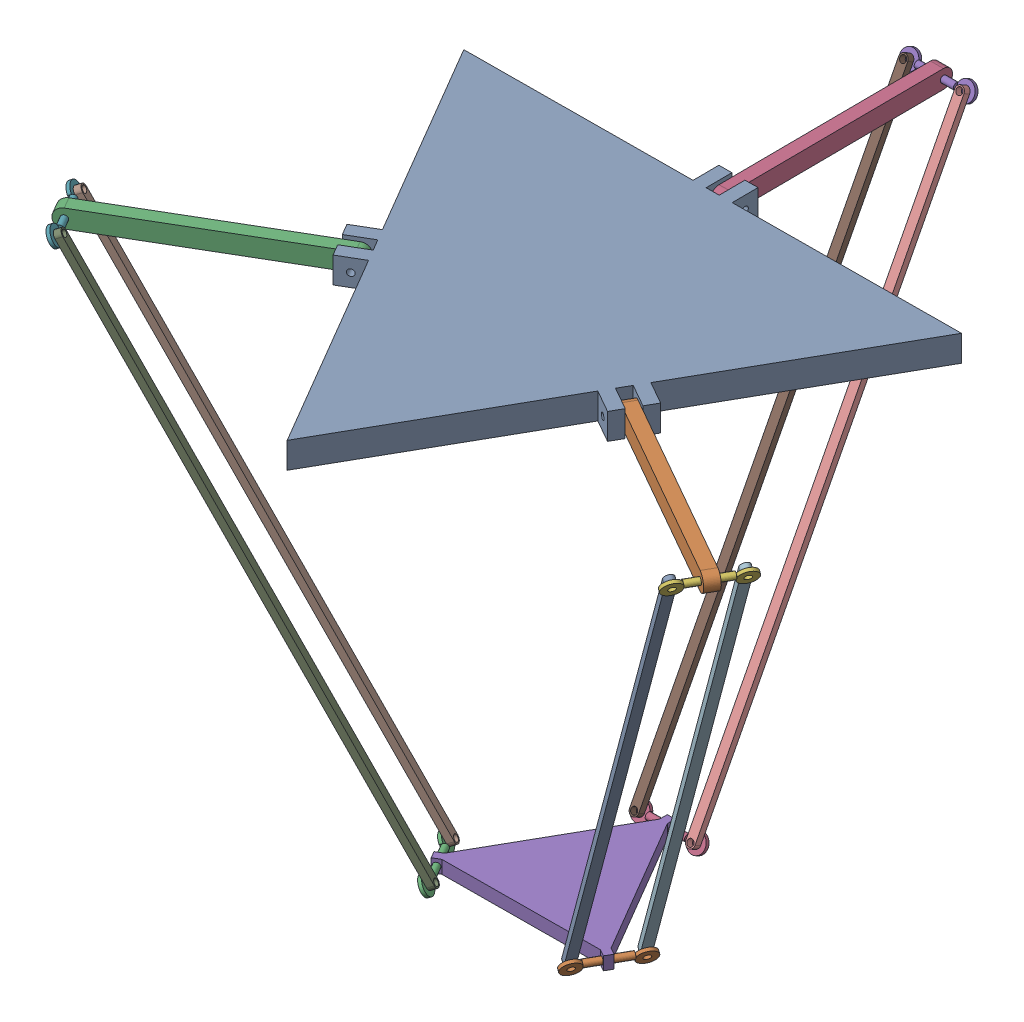
SolidWorks assembly deltafinal, configuration Default. Lengths in mm.
Overall size (529.94 413.54 512.31).
17 component instances, 5 part files, 44 mates.
Components (placement in the parent):
- Base_triangulo_cima-1: Base_triangulo_cima [Default] at (0 -20 0) x (0.999979 0 -0.006522) z (0.006522 0 0.999979) size (381.1 20 350.04)
- Barra_cima-1: Barra_cima [Default] at (104.3244 -10 59.3279) x (0.869268 0 0.494341) z (-0.494341 0 0.869268) size (178 14 10)
- Barra_cima-2: Barra_cima [Default] at (-245.0321 -10 143.6081) x (0.862746 0 -0.505637) z (0.505637 0 0.862746) size (178 14 10)
- Barra_cima-3: Barra_cima [Default] at (-1.8523 -10 -284.0081) x (0.006522 0 0.999979) z (-0.999979 0 0.006522) size (178 14 10)
- entre_barras1-1: entre_barras1 [Default] at (-1.8523 -10 -284.0081) x (0.999979 0 -0.006522) z (0.005767 0.466869 0.884308) size (57.08 14 5)
- entre_barras1-2: entre_barras1 [Default] at (246.8843 -10 140.3999) x (-0.494341 0 0.869268) z (-0.768717 0.466869 -0.437159) size (57.08 14 5)
- entre_barras1-3: entre_barras1 [Default] at (-245.0321 -10 143.6081) x (-0.505637 0 -0.862746) z (0.762949 0.466869 -0.447149) size (57.08 14 5)
- Barra_baixo-1: Barra_baixo [Default] at (-254.0153 -8.8328 123.9081) x (0.506087 -0.000987 0.862482) z (-0.762949 -0.466869 0.447149) size (7 455 5)
- Barra_baixo-2: Barra_baixo [Default] at (-232.2341 -8.8328 161.0724) x (0.506087 -0.000987 0.862482) z (-0.762949 -0.466869 0.447149) size (7 455 5)
- Barra_baixo-3: Barra_baixo [Default] at (19.7 -8.8328 -281.9378) x (0.999975 0.000987 -0.007043) z (0.005767 0.466869 0.884308) size (7 455 5)
- Barra_baixo-4: Barra_baixo [Default] at (-23.3757 -8.8328 -281.6568) x (0.999975 0.000987 -0.007043) z (0.005767 0.466869 0.884308) size (7 455 5)
- Barra_baixo-5: Barra_baixo [Default] at (255.6098 -8.8328 120.5844) x (0.494794 0.000987 -0.86901) z (0.768717 -0.466869 0.437159) size (7 455 5)
- Barra_baixo-6: Barra_baixo [Default] at (234.3152 -8.8328 158.0296) x (0.494794 0.000987 -0.86901) z (0.768717 -0.466869 0.437159) size (7 455 5)
- entre_barras1-4: entre_barras1 [Default] at (65.318 -406.1781 36.5703) x (-0.494341 0 0.869268) z (-0.768717 0.466869 -0.437159) size (57.08 14 5)
- entre_barras1-5: entre_barras1 [Default] at (-64.8354 -406.1781 37.4191) x (-0.505637 0 -0.862746) z (0.762949 0.466869 -0.447149) size (57.08 14 5)
- entre_barras1-6: entre_barras1 [Default] at (0.0118 -406.1781 -74.8587) x (0.999979 0 -0.006522) z (0.005767 0.466869 0.884308) size (57.08 14 5)
- base_baixo-1: base_baixo [Default] at (0.2513 -411.1781 38.5258) x (0.999979 0 -0.006522) z (0.006522 0 0.999979) size (137.85 10 119.38)
Mates (geometry in assembly coordinates):
- Concentric1: concentric anti-aligned: cylinder of Base_triangulo_cima-1 through (115.235 -10 40.1423) axis (-0.494341 0 0.869268) radius 2.5; cylinder of Barra_cima-1 through (101.8527 -10 63.6743) axis (0.494341 0 -0.869268) radius 2.5
- Concentric2: concentric anti-aligned: cylinder of Base_triangulo_cima-1 through (115.235 -10 40.1423) axis (-0.494341 0 0.869268) radius 2.5; cylinder of Barra_cima-1 through (101.8527 -10 63.6743) axis (0.494341 0 -0.869268) radius 2.5
- Coincident1: coincident anti-aligned: plane of Base_triangulo_cima-1 through (110.5454 0 68.6177) normal (0.494341 0 -0.869268); plane of Barra_cima-1 through (101.8527 -10 63.6743) normal (-0.494341 0 0.869268)
- Concentric3: concentric anti-aligned: cylinder of Base_triangulo_cima-1 through (-229.181 -10 -153.6891) axis (0.505637 0 0.862746) radius 2.5; cylinder of Barra_cima-2 through (-101.0135 -10 64.9973) axis (-0.505637 0 -0.862746) radius 2.5
- Concentric4: concentric anti-aligned: cylinder of Base_triangulo_cima-1 through (-229.181 -10 -153.6891) axis (0.505637 0 0.862746) radius 2.5; cylinder of Barra_cima-2 through (-101.0135 -10 64.9973) axis (-0.505637 0 -0.862746) radius 2.5
- Coincident2: coincident anti-aligned: plane of Base_triangulo_cima-1 through (-114.6973 0 61.4263) normal (0.505637 0 0.862746); plane of Barra_cima-2 through (-247.5602 -10 139.2944) normal (-0.505637 0 -0.862746)
- Concentric5: concentric anti-aligned: cylinder of Base_triangulo_cima-1 through (157.691 -10 -121.0451) axis (-0.999979 0 0.006522) radius 2.5; cylinder of Barra_cima-3 through (-5.7826 -10 -119.9789) axis (0.999979 0 -0.006522) radius 2.5
- Concentric6: concentric anti-aligned: cylinder of Base_triangulo_cima-1 through (157.691 -10 -121.0451) axis (-0.999979 0 0.006522) radius 2.5; cylinder of Barra_cima-3 through (-5.7826 -10 -119.9789) axis (0.999979 0 -0.006522) radius 2.5
- Coincident3: coincident anti-aligned: plane of Base_triangulo_cima-1 through (4.152 0 -130.0439) normal (-0.999979 0 0.006522); plane of Barra_cima-3 through (3.1476 -10 -284.0407) normal (0.999979 0 -0.006522)
- Concentric8: concentric anti-aligned: cylinder of Barra_cima-3 through (-6.8522 -10 -283.9754) axis (0.999979 0 -0.006522) radius 2.5; cylinder of entre_barras1-1 through (-16.8519 -10 -283.9102) axis (-0.999979 0 0.006522) radius 2.5
- Distance2: distance = 10 mm anti-aligned: plane of entre_barras1-1 through (-16.8588 -13.378 -284.9539) normal (0.999979 0 -0.006522); plane of Barra_cima-3 through (-6.8522 -10 -283.9754) normal (-0.999979 0 0.006522)
- Concentric10: concentric aligned: cylinder of Barra_cima-1 through (244.4126 -10 144.7463) axis (0.494341 0 -0.869268) radius 2.5; cylinder of entre_barras1-2 through (254.2994 -10 127.3609) axis (0.494341 0 -0.869268) radius 2.5
- Distance3: distance = 10 mm anti-aligned: plane of entre_barras-2 through (255.2066 -13.378 127.8768) normal (-0.494341 0 0.869268); plane of Barra_cima-1 through (106.7961 -10 54.9816) normal (0.494341 0 -0.869268)
- Concentric11: concentric anti-aligned: cylinder of Barra_cima-2 through (-242.5039 -10 147.9219) axis (-0.505637 0 -0.862746) radius 2.5; cylinder of entre_barras1-3 through (-237.4475 -10 156.5493) axis (0.505637 0 0.862746) radius 2.5
- Distance4: distance = 10 mm anti-aligned: plane of entre_barras1-3 through (-238.3479 -13.378 157.077) normal (-0.505637 0 -0.862746); plane of Barra_cima-2 through (-242.5039 -10 147.9219) normal (0.505637 0 0.862746)
- Concentric12: concentric aligned: cylinder of entre_barras1-3 through (-257.83 -11.1672 126.1439) axis (0.762949 0.466869 -0.447149) radius 2.5; cylinder of Barra_baixo-1 through (-255.9227 -10 125.026) axis (0.762949 0.466869 -0.447149) radius 2.5
- Coincident13: coincident anti-aligned: plane of entre_barras1-3 through (-255.9227 -10 125.026) normal (0.762949 0.466869 -0.447149); plane of Barra_baixo-1 through (-255.9227 -10 125.026) normal (-0.762949 -0.466869 0.447149)
- Concentric13: concentric aligned: cylinder of entre_barras1-3 through (-236.0488 -11.1672 163.3081) axis (0.762949 0.466869 -0.447149) radius 2.5; cylinder of Barra_baixo-2 through (-234.1415 -10 162.1903) axis (0.762949 0.466869 -0.447149) radius 2.5
- Coincident14: coincident anti-aligned: plane of entre_barras1-3 through (-234.1415 -10 162.1903) normal (0.762949 0.466869 -0.447149); plane of Barra_baixo-2 through (-234.1415 -10 162.1903) normal (-0.762949 -0.466869 0.447149)
- Concentric14: concentric anti-aligned: cylinder of entre_barras1-1 through (19.6712 -11.1672 -286.3593) axis (0.005767 0.466869 0.884308) radius 2.5; cylinder of Barra_baixo-3 through (19.7145 -7.6657 -279.727) axis (-0.005767 -0.466869 -0.884308) radius 2.5
- Coincident15: coincident anti-aligned: plane of entre_barras1-1 through (19.6856 -10 -284.1485) normal (0.005767 0.466869 0.884308); plane of Barra_baixo-3 through (19.6856 -10 -284.1485) normal (-0.005767 -0.466869 -0.884308)
- Concentric15: concentric anti-aligned: cylinder of entre_barras1-1 through (-23.4046 -11.1672 -286.0784) axis (0.005767 0.466869 0.884308) radius 2.5; cylinder of Barra_baixo-4 through (-23.3613 -7.6657 -279.446) axis (-0.005767 -0.466869 -0.884308) radius 2.5
- Coincident16: coincident anti-aligned: plane of entre_barras1-1 through (-23.3902 -10 -283.8676) normal (0.005767 0.466869 0.884308); plane of Barra_baixo-4 through (-23.3902 -10 -283.8676) normal (-0.005767 -0.466869 -0.884308)
- Concentric16: concentric aligned: cylinder of entre_barras1-2 through (259.4534 -11.1672 122.7702) axis (-0.768717 0.466869 -0.437159) radius 2.5; cylinder of Barra_baixo-5 through (257.5316 -10 121.6773) axis (-0.768717 0.466869 -0.437159) radius 2.5
- Coincident17: coincident anti-aligned: plane of entre_barras1-2 through (257.5316 -10 121.6773) normal (-0.768717 0.466869 -0.437159); plane of Barra_baixo-5 through (257.5316 -10 121.6773) normal (0.768717 -0.466869 0.437159)
- Concentric17: concentric aligned: cylinder of entre_barras1-2 through (238.1588 -11.1672 160.2154) axis (-0.768717 0.466869 -0.437159) radius 2.5; cylinder of Barra_baixo-6 through (236.237 -10 159.1225) axis (-0.768717 0.466869 -0.437159) radius 2.5
- Coincident18: coincident anti-aligned: plane of entre_barras1-2 through (236.237 -10 159.1225) normal (-0.768717 0.466869 -0.437159); plane of Barra_baixo-6 through (236.237 -10 159.1225) normal (0.768717 -0.466869 0.437159)
- Concentric18: concentric aligned: cylinder of Barra_baixo-5 through (75.9653 -406.1781 17.8477) axis (-0.768717 0.466869 -0.437159) radius 2.5; cylinder of entre_barras1-4 through (77.8871 -407.3452 18.9406) axis (-0.768717 0.466869 -0.437159) radius 2.5
- Concentric19: concentric aligned: cylinder of Barra_baixo-6 through (54.6707 -406.1781 55.2929) axis (-0.768717 0.466869 -0.437159) radius 2.5; cylinder of entre_barras1-4 through (56.5925 -407.3452 56.3858) axis (-0.768717 0.466869 -0.437159) radius 2.5
- Coincident19: coincident anti-aligned: plane of Barra_baixo-6 through (236.237 -10 159.1225) normal (0.768717 -0.466869 0.437159); plane of entre_barras1-4 through (54.6707 -406.1781 55.2929) normal (-0.768717 0.466869 -0.437159)
- Concentric20: concentric aligned: cylinder of Barra_baixo-2 through (-53.9448 -406.1781 56.0013) axis (0.762949 0.466869 -0.447149) radius 2.5; cylinder of entre_barras1-5 through (-55.8522 -407.3452 57.1191) axis (0.762949 0.466869 -0.447149) radius 2.5
- Concentric21: concentric aligned: cylinder of Barra_baixo-1 through (-75.726 -406.1781 18.837) axis (0.762949 0.466869 -0.447149) radius 2.5; cylinder of entre_barras1-5 through (-77.6334 -407.3452 19.9549) axis (0.762949 0.466869 -0.447149) radius 2.5
- Coincident22: coincident anti-aligned: plane of Barra_baixo-2 through (-234.1415 -10 162.1903) normal (-0.762949 -0.466869 0.447149); plane of entre_barras1-5 through (-53.9448 -406.1781 56.0013) normal (0.762949 0.466869 -0.447149)
- Concentric22: concentric anti-aligned: cylinder of Barra_baixo-4 through (-21.4973 -403.8437 -70.2967) axis (-0.005767 -0.466869 -0.884308) radius 2.5; cylinder of entre_barras1-6 through (-21.5405 -407.3452 -76.929) axis (0.005767 0.466869 0.884308) radius 2.5
- Concentric23: concentric anti-aligned: cylinder of Barra_baixo-3 through (21.5785 -403.8437 -70.5776) axis (-0.005767 -0.466869 -0.884308) radius 2.5; cylinder of entre_barras1-6 through (21.5353 -407.3452 -77.2099) axis (0.005767 0.466869 0.884308) radius 2.5
- Coincident23: coincident anti-aligned: plane of Barra_baixo-4 through (-23.3902 -10 -283.8676) normal (-0.005767 -0.466869 -0.884308); plane of entre_barras1-6 through (-21.5261 -406.1781 -74.7182) normal (0.005767 0.466869 0.884308)
- Concentric24: concentric aligned: cylinder of entre_barras1-6 through (-14.9879 -406.1781 -74.7609) axis (-0.999979 0 0.006522) radius 2.5; cylinder of base_baixo-1 through (9.5827 -406.1781 -74.9211) axis (-0.999979 0 0.006522) radius 2.5
- Concentric25: concentric aligned: cylinder of entre_barras1-5 through (-57.2509 -406.1781 50.3603) axis (0.505637 0 0.862746) radius 2.5; cylinder of base_baixo-1 through (-69.6749 -406.1781 29.1617) axis (0.505637 0 0.862746) radius 2.5
- Distance6: distance = 12.5 mm anti-aligned: plane of entre_barras1-5 through (-75.3343 -405.1344 26.186) normal (0.505637 0 0.862746); plane of base_baixo-1 through (-63.5113 -401.1781 33.7454) normal (-0.505637 0 -0.862746)
- Concentric26: concentric anti-aligned: cylinder of entre_barras1-4 through (72.7331 -406.1781 23.5313) axis (0.494341 0 -0.869268) radius 2.5; cylinder of base_baixo-1 through (137.3745 -406.1781 -90.1366) axis (-0.494341 0 0.869268) radius 2.5
- Distance7: distance = 12.5 mm anti-aligned: plane of base_baixo-1 through (63.946 -401.1781 32.9141) normal (0.494341 0 -0.869268); plane of entre_barras1-4 through (73.6403 -409.5561 24.0472) normal (-0.494341 0 0.869268)
- Distance8: distance = 12.5 mm anti-aligned: plane of entre_barras1-6 through (14.9894 -405.1344 -78.3344) normal (-0.999979 0 0.006522); plane of base_baixo-1 through (2.5313 -401.1781 -71.8751) normal (0.999979 0 -0.006522)
- Coincident27: coincident aligned: plane of Base_triangulo_cima-1 through (0 0 0) normal (0 1 0)
- Parallel2: parallel aligned: plane of Base_triangulo_cima-1 through (0 0 0) normal (0 1 0); plane of base_baixo-1 through (0.2513 -401.1781 38.5258) normal (0 1 0)
